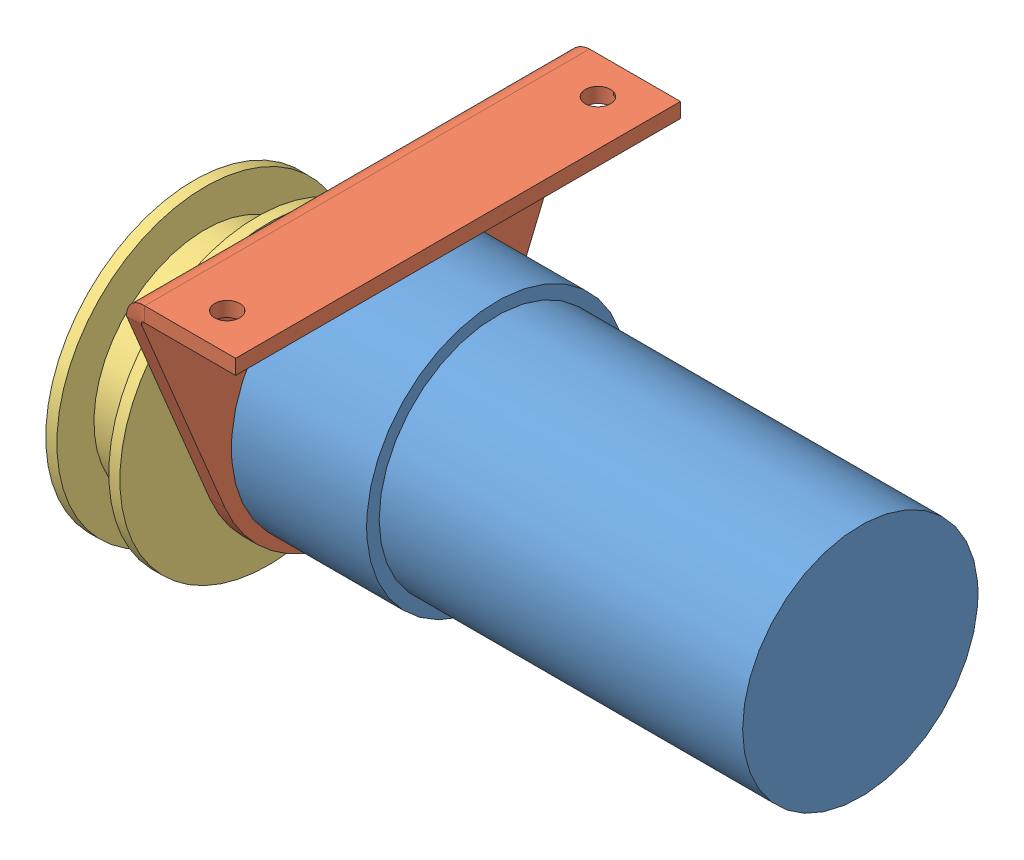
SolidWorks assembly Brush Drive, configuration Default. Lengths in mm.
Overall size (89.87 64.34 48.21).
3 component instances, 3 part files, 5 mates.
Components (placement in the parent):
- Motor Barber Coleman geared-1: Motor Barber Coleman geared [Default] at (-9.5723 1.7114 1.7306) size (89.87 35.14 35.14)
- Brush Drive Motor Mount-1: Brush Drive Motor Mount [Default] at (-27.8095 2.9928 1.7306) x (1 0 0) z (0 0 -1) size (0.7 50.23 40)
- Brush Motor Belt Gear-1: Brush Motor Belt Gear [Default] at (-45.4155 -7.0072 1.7306) x (1 0 0) z (0 -0.232587 0.972576) size (10 40 40)
Mates (geometry in assembly coordinates):
- Coincident2: coincident anti-aligned: plane of Motor Barber Coleman geared-1 through (-27.8095 1.7114 1.7306) normal (-1 0 0); plane of Brush Drive Motor Mount-1 through (-27.8095 2.9928 1.7306) normal (1 0 0)
- Concentric3: concentric anti-aligned: circle of Motor Barber Coleman geared-1; circle of Brush Drive Motor Mount-1
- Concentric4: concentric anti-aligned: circle of Motor Barber Coleman geared-1; circle of Brush Drive Motor Mount-1
- Coincident3: coincident anti-aligned: plane of Motor Barber Coleman geared-1 through (-35.4295 -3.9465 -3.8055) normal (0 0.972576 0.232587); plane of Brush Motor Belt Gear-1 through (-50.4155 -5.3644 2.1234) normal (0 -0.972576 -0.232587)
- Coincident4: coincident anti-aligned: circle of Motor Barber Coleman geared-1; circle of Brush Motor Belt Gear-1
